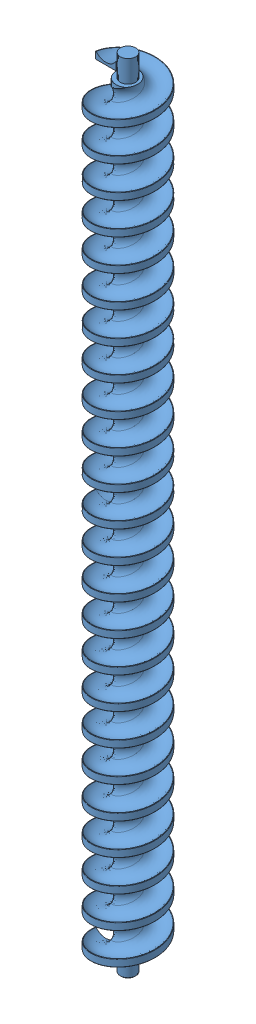
SolidWorks assembly screw_stack, configuration Default. Lengths in mm.
Overall size (27.55 316.86 27.54).
2 component instances, 1 part files, 3 mates.
Components (placement in the parent):
- screw02-1: screw02 [bottom] at (-23.7652 -60.3589 2.0065) size (27.55 164.46 27.54)
- screw02-2: screw02 [top] at (-23.7652 92.0411 2.0065) x (1 0 -0.000075) z (0.000075 0 1) size (27.55 170.81 27.54)
Mates (geometry in assembly coordinates):
- Coincident3: coincident: plane of assembly; plane of assembly; plane of screw02-1 through (-36.7827 92.8348 2.0065) normal (0 0 1); plane of screw02-2 through (-36.7827 94.4222 2.0065) normal (0 0 -1)
- Concentric2: concentric: cylinder of assembly; cylinder of assembly; cylinder of screw02-1 through (-23.7652 85.4371 2.0065) axis (0 1 0) radius 3.175; cylinder of screw02-2 through (-23.7652 85.6911 2.0065) axis (0 1 0) radius 3.1115
- Coincident4: coincident: plane of assembly; plane of assembly; plane of screw02-1 through (-23.7652 92.0411 2.0065) normal (0 1 0); plane of screw02-2 through (-23.7652 92.0411 2.0065) normal (0 -1 0)
